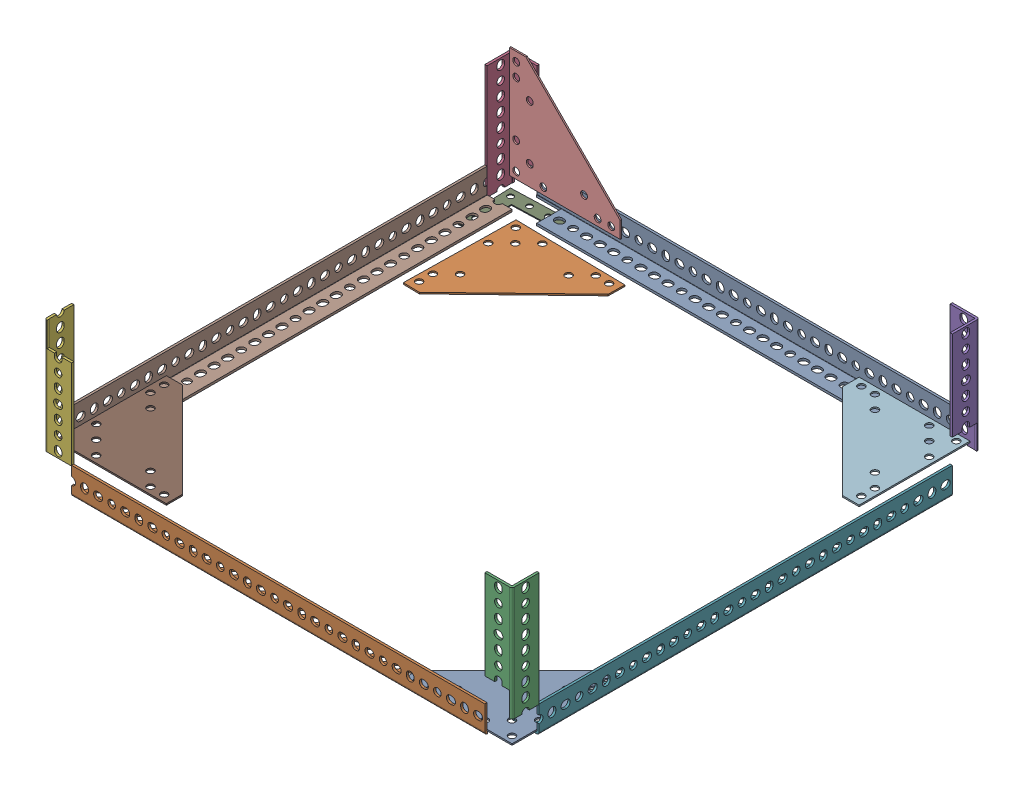
SolidWorks assembly TestBuild, configuration Default. Lengths in mm.
Overall size (656.2 204.55 656.2).
14 component instances, 4 part files, 25 mates.
Components (placement in the parent):
- Longitudinal_piece-1: Longitudinal_piece [4664T425] at (1553.3808 889.5554 1273.3491) size (580 38.1 38.1)
- Longitudinal_piece-2: Longitudinal_piece [4664T425] at (-305.0192 851.9934 1891.4491) x (-1 0 0) z (0 0 -1) size (580 38.1 38.1)
- Lateral_piece-3: Lateral_piece [Default] at (933.2308 231.2964 1891.4491) x (0 -1 0) z (0 0 -1) size (160 38.1 38.1)
- Lateral_piece-4: Lateral_piece [Default] at (315.1308 231.0694 1273.3491) x (0 -1 0) z (0 0 1) size (160 38.1 38.1)
- Lateral_piece-5: Lateral_piece [Default] at (933.2308 231.4754 1273.3491) x (0 -1 0) z (-1 0 0) size (160 38.1 38.1)
- Lateral_piece-6: Lateral_piece [Default] at (315.1308 1669.2073 1891.4491) x (0 1 0) z (0 0 -1) size (160 38.1 38.1)
- Longitudinal_piece-4: Longitudinal_piece [4664T425] at (933.2308 851.9934 2511.5991) x (0 0 1) z (-1 0 0) size (580 38.1 38.1)
- Longitudinal_piece-5: Longitudinal_piece [4664T425] at (315.1308 889.1498 653.1991) x (0 0 -1) z (1 0 0) size (580 38.1 38.1)
- L_bracket-1: L_bracket [Default] at (304.4082 870.5054 1264.8409) x (0.999423 0 -0.033966) z (-0.033966 0 -0.999423) size (80 1.19 80)
- 4664T407_Bolt-Together Framing-1: 4664T407_Bolt-Together Framing [4664T407] at (377.6596 959.7078 1260.7142) size (155.57 155.57 2.03)
- 4664T407_Bolt-Together Framing-2: 4664T407_Bolt-Together Framing [4664T407] at (383.7798 884.4295 1827.2097) x (1 0 0) z (0 1 0) size (155.57 155.57 2.03)
- 4664T407_Bolt-Together Framing-3: 4664T407_Bolt-Together Framing [4664T407] at (866.678 879.3278 1337.6524) x (-1 0 0) z (0 1 0) size (155.57 155.57 2.03)
- 4664T407_Bolt-Together Framing-4: 4664T407_Bolt-Together Framing [4664T407] at (871.3183 837.5154 1829.5366) x (-1 0 0) z (0 -1 0) size (155.57 155.57 2.03)
- 4664T407_Bolt-Together Framing-5: 4664T407_Bolt-Together Framing [4664T407] at (415.0985 861.1701 1370.4117) x (0.999848 0 0.017452) z (0 -1 0) size (155.57 155.57 2.03)
Mates (geometry in assembly coordinates):
- Parallel2: parallel anti-aligned: line of Longitudinal_piece-1 through (914.1808 873.6804 1292.3991) axis (-1 0 0); line of Longitudinal_piece-2 through (334.1808 836.1184 1872.3991) axis (1 0 0)
- Coincident27: coincident: line of Longitudinal_piece-2 through (334.1808 836.1184 1896.7831) axis (0 0 1); line of Longitudinal_piece-1 through (334.1808 873.6804 1257.8551) axis (0 0 1)
- Coincident35: coincident anti-aligned: line of Longitudinal_piece-2 through (914.1808 871.0434 1907.3241) axis (0 -1 0); line of Lateral_piece-3 through (914.1808 904.9964 1907.3241) axis (0 1 0)
- Coincident36: coincident anti-aligned: line of Longitudinal_piece-1 through (914.1808 908.6054 1254.2991) axis (0 -1 0); line of Lateral_piece-5 through (914.1808 870.6754 1254.2991) axis (0 1 0)
- Coincident39: coincident aligned: line of Longitudinal_piece-1 through (334.1808 874.0614 1254.2991) axis (0 1 0); line of Lateral_piece-4 through (334.1808 904.7694 1254.2991) axis (0 1 0)
- Coincident48: coincident aligned: line of Longitudinal_piece-2 through (334.1808 846.6594 1910.4991) axis (0 -1 0); line of Lateral_piece-6 through (334.1808 995.5073 1910.4991) axis (0 -1 0)
- Coincident51: coincident anti-aligned: line of Lateral_piece-6 through (296.0808 1030.0073 1872.3991) axis (0 -1 0); line of Longitudinal_piece-5 through (296.0808 873.6558 1872.3991) axis (0 1 0)
- Coincident52: coincident aligned: line of Lateral_piece-4 through (299.2558 870.2694 1292.3991) axis (0 1 0); line of Longitudinal_piece-5 through (299.2558 894.4838 1292.3991) axis (0 1 0)
- Coincident53: coincident aligned: line of Lateral_piece-5 through (952.2808 905.1754 1292.3991) axis (0 1 0); line of Longitudinal_piece-4 through (952.2808 836.4994 1292.3991) axis (0 1 0)
- Coincident54: coincident anti-aligned: line of Lateral_piece-3 through (952.2808 870.4964 1872.3991) axis (0 1 0); line of Longitudinal_piece-4 through (952.2808 846.6594 1872.3991) axis (0 -1 0)
- Coincident55: coincident anti-aligned: plane of Longitudinal_piece-1 through (2772.5808 870.5054 1257.8551) normal (0 -1 0); plane of L_bracket-1 through (304.4082 870.5054 1264.8409) normal (0 1 0)
- Coincident89: coincident: line of Longitudinal_piece-1 through (914.1808 908.6054 1254.2991) axis (0 -1 0); plane of Lateral_piece-5 through (948.7248 -987.7246 1254.2991) normal (0 0 -1)
- Coincident90: coincident aligned: line of Longitudinal_piece-1 through (914.1808 894.8893 1257.4741) axis (0 1 0); line of Lateral_piece-5 through (914.1808 870.6754 1257.4741) axis (0 1 0)
- Coincident91: coincident anti-aligned: line of Lateral_piece-5 through (949.1058 905.1754 1292.3991) axis (0 1 0); line of Longitudinal_piece-4 through (949.1058 871.0434 1292.3991) axis (0 -1 0)
- Coincident92: coincident aligned: line of Lateral_piece-5 through (952.2808 905.1754 1292.3991) axis (0 1 0); line of Longitudinal_piece-4 through (952.2808 836.4994 1292.3991) axis (0 1 0)
- Coincident93: coincident aligned: line of Lateral_piece-3 through (949.1058 870.4964 1872.3991) axis (0 1 0); line of Longitudinal_piece-4 through (949.1058 857.3274 1872.3991) axis (0 1 0)
- Coincident94: coincident anti-aligned: line of Lateral_piece-3 through (952.2808 870.4964 1872.3991) axis (0 1 0); line of Longitudinal_piece-4 through (952.2808 871.0434 1872.3991) axis (0 -1 0)
- Coincident95: coincident aligned: line of Longitudinal_piece-2 through (914.1808 836.4994 1910.4991) axis (0 1 0); line of Lateral_piece-3 through (914.1808 904.9964 1910.4991) axis (0 1 0)
- Coincident96: coincident anti-aligned: line of Longitudinal_piece-2 through (914.1808 871.0434 1907.3241) axis (0 -1 0); line of Lateral_piece-3 through (914.1808 904.9964 1907.3241) axis (0 1 0)
- Coincident97: coincident anti-aligned: line of Lateral_piece-6 through (296.0808 1030.0073 1872.3991) axis (0 -1 0); line of Longitudinal_piece-5 through (296.0808 873.6558 1872.3991) axis (0 1 0)
- Coincident98: coincident aligned: line of Lateral_piece-6 through (299.2558 1030.0073 1872.3991) axis (0 -1 0); line of Longitudinal_piece-5 through (299.2558 908.1998 1872.3991) axis (0 -1 0)
- Coincident99: coincident aligned: line of Longitudinal_piece-2 through (334.1808 871.0434 1910.4991) axis (0 -1 0); line of Lateral_piece-6 through (334.1808 995.5073 1910.4991) axis (0 -1 0)
- Coincident100: coincident anti-aligned: line of Longitudinal_piece-2 through (334.1808 857.3274 1907.3241) axis (0 1 0); line of Lateral_piece-6 through (334.1808 995.5073 1907.3241) axis (0 -1 0)
- Coincident106: coincident anti-aligned: line of Longitudinal_piece-2 through (334.1808 836.4994 1907.3241) axis (1 0 0); line of 4664T407_Bolt-Together Framing-4 through (949.1058 836.4994 1907.3241) axis (-1 0 0)
- Coincident107: coincident anti-aligned: line of Longitudinal_piece-4 through (949.1058 836.4994 1872.3991) axis (0 0 -1); line of 4664T407_Bolt-Together Framing-4 through (949.1058 836.4994 1751.7491) axis (0 0 1)
